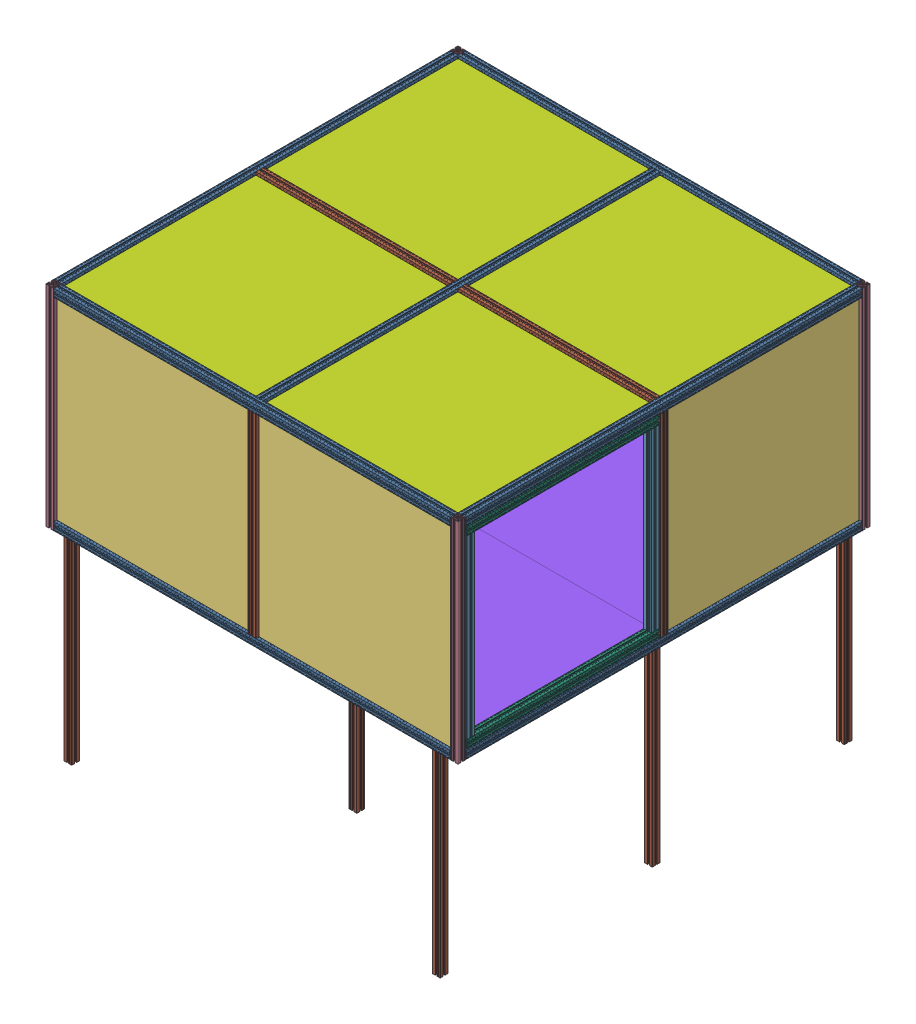
SolidWorks assembly Arena_Mod_Clean, configuration Valor predeterminado. Lengths in mm.
Overall size (2080 2040 2080).
64 component instances, 8 part files, 4 mates.
Components (placement in the parent):
- Lateral_S_Porta_Mod2-1: Lateral_S_Porta_Mod2 [Valor predeterminado] at (857.6684 -517.9892 5370.6056) size (2020 2040 40)
  - Perfil_Alum_4x4x200-1: Perfil_Alum_4x4x200 [Valor predeterminado] at (40.4856 -17.0967 -270.6056) x (0 0 -1) z (1 0 0) size (40 40 2000)
  - Perfil_Alum_4x4x200-2: Perfil_Alum_4x4x200 [Valor predeterminado] at (40.4856 1002.9033 -270.6056) x (0 0 -1) z (1 0 0) size (40 40 2000)
  - Perfil_Alum_4x4x98-1: Perfil_Alum_4x4x98 [Valor predeterminado] at (40.4856 492.9033 -270.6056) x (1 0 0) z (0 -1 0) size (40 40 980)
  - Policarbonato 1x1-1: Policarbonato 1x1 [Valor predeterminado] at (550.4856 492.9033 -270.6056) size (1000 1000 6)
  - Policarbonato 1x1-2: Policarbonato 1x1 [Valor predeterminado] at (-469.5144 492.9033 -270.6056) size (1000 1000 6)
  - Perfil_Alum_4x4x98-2: Perfil_Alum_4x4x98 [Valor predeterminado] at (-889.5144 -527.0967 -270.6056) x (1 0 0) z (0 -1 0) size (40 40 980)
  - Perfil_Alum_4x4x98-3: Perfil_Alum_4x4x98 [Valor predeterminado] at (970.4856 -527.0967 -270.6056) x (1 0 0) z (0 -1 0) size (40 40 980)
- Lateral_C_Porta_Mod2-2: Lateral_C_Porta_Mod2 [Valor predeterminado] at (1960.4084 -532.8569 2080) size (40 1060 2080)
  - Perfil_Alum_4x4x200-1: Perfil_Alum_4x4x200 [Valor predeterminado] at (-42.2544 -2.229 2000) size (40 40 2000)
  - Perfil_Alum_4x4x106-1: Perfil_Alum_4x4x106 [Valor predeterminado] at (-42.2544 507.771 3020) x (1 0 0) z (0 -1 0) size (40 40 1060)
  - Perfil_Alum_4x4x98-1: Perfil_Alum_4x4x98 [Valor predeterminado] at (-42.2544 507.771 2000) x (1 0 0) z (0 -1 0) size (40 40 980)
  - Perfil_Alum_4x4x106-2: Perfil_Alum_4x4x106 [Valor predeterminado] at (-42.2544 507.771 980) x (1 0 0) z (0 -1 0) size (40 40 1060)
  - Perfil_Alum_4x4x200-2: Perfil_Alum_4x4x200 [Valor predeterminado] at (-42.2544 1017.771 2000) size (40 40 2000)
  - Porta_Mod_Clean-1: Porta_Mod_Clean [Valor predeterminado] at (-25.965 113.1173 1603.2592) size (40 970 970)
    - Perfil_Alum_4x4x89-1: Perfil_Alum_4x4x89 [Valor predeterminado] at (-16.2893 394.6537 1371.7408) x (1 0 0) z (0 -1 0) size (40 40 890)
    - Perfil_Alum_4x4x97-1: Perfil_Alum_4x4x97 [Valor predeterminado] at (-16.2893 -70.3463 906.7408) size (40 40 970)
    - Perfil_Alum_4x4x97-2: Perfil_Alum_4x4x97 [Valor predeterminado] at (-16.2893 859.6537 906.7408) size (40 40 970)
    - Perfil_Alum_4x4x89-2: Perfil_Alum_4x4x89 [Valor predeterminado] at (-16.2893 394.6537 441.7408) x (1 0 0) z (0 -1 0) size (40 40 890)
  - Policarbonato 1x1-1: Policarbonato 1x1 [Valor predeterminado] at (-42.2544 507.771 1490) x (0 0 -1) z (1 0 0) size (1000 1000 6)
- Lateral_S_Porta_Mod2-2: Lateral_S_Porta_Mod2 [Valor predeterminado] at (857.6684 -517.9892 3330.6056) size (2020 2040 40)
  - Perfil_Alum_4x4x200-1: Perfil_Alum_4x4x200 [Valor predeterminado] at (40.4856 -17.0967 -270.6056) x (0 0 -1) z (1 0 0) size (40 40 2000)
  - Perfil_Alum_4x4x200-2: Perfil_Alum_4x4x200 [Valor predeterminado] at (40.4856 1002.9033 -270.6056) x (0 0 -1) z (1 0 0) size (40 40 2000)
  - Perfil_Alum_4x4x98-1: Perfil_Alum_4x4x98 [Valor predeterminado] at (40.4856 492.9033 -270.6056) x (1 0 0) z (0 -1 0) size (40 40 980)
  - Policarbonato 1x1-1: Policarbonato 1x1 [Valor predeterminado] at (550.4856 492.9033 -270.6056) size (1000 1000 6)
  - Policarbonato 1x1-2: Policarbonato 1x1 [Valor predeterminado] at (-469.5144 492.9033 -270.6056) size (1000 1000 6)
  - Perfil_Alum_4x4x98-2: Perfil_Alum_4x4x98 [Valor predeterminado] at (-889.5144 -527.0967 -270.6056) x (1 0 0) z (0 -1 0) size (40 40 980)
  - Perfil_Alum_4x4x98-3: Perfil_Alum_4x4x98 [Valor predeterminado] at (970.4856 -527.0967 -270.6056) x (1 0 0) z (0 -1 0) size (40 40 980)
- Teto_Mod_Clean-1: Teto_Mod_Clean [Valor predeterminado] at (1160.5083 2484.9141 4086.7617) size (2020 40 2020)
  - Perfil_Alum_4x4x200-1: Perfil_Alum_4x4x200 [Valor predeterminado] at (-262.3542 -2000 -6.7617) size (40 40 2000)
  - Perfil_Alum_4x4x98-1: Perfil_Alum_4x4x98 [Valor predeterminado] at (-772.3542 -2000 -6.7617) x (0 0 -1) z (1 0 0) size (40 40 980)
  - Perfil_Alum_4x4x98-2: Perfil_Alum_4x4x98 [Valor predeterminado] at (247.6458 -2000 -6.7617) x (0 0 -1) z (1 0 0) size (40 40 980)
  - Policarbonato_Teto-1: Policarbonato_Teto [Valor predeterminado] at (-772.3542 -2000 -516.7617) size (1000 6 1000)
  - Policarbonato_Teto-2: Policarbonato_Teto [Valor predeterminado] at (-772.3542 -2000 503.2383) x (0 0 -1) z (1 0 0) size (1000 6 1000)
  - Policarbonato_Teto-3: Policarbonato_Teto [Valor predeterminado] at (247.6458 -2000 503.2383) x (-1 0 0) z (0 0 -1) size (1000 6 1000)
  - Policarbonato_Teto-4: Policarbonato_Teto [Valor predeterminado] at (247.6458 -2000 -516.7617) x (0 0 1) z (-1 0 0) size (1000 6 1000)
- Lateral_C_Porta_Mod2-3: Lateral_C_Porta_Mod2 [Valor predeterminado] at (-164.1003 -532.8569 6080) x (-1 0 0) z (0 0 -1) size (40 1060 2080)
  - Perfil_Alum_4x4x200-1: Perfil_Alum_4x4x200 [Valor predeterminado] at (-42.2544 -2.229 2000) size (40 40 2000)
  - Perfil_Alum_4x4x106-1: Perfil_Alum_4x4x106 [Valor predeterminado] at (-42.2544 507.771 3020) x (1 0 0) z (0 -1 0) size (40 40 1060)
  - Perfil_Alum_4x4x98-1: Perfil_Alum_4x4x98 [Valor predeterminado] at (-42.2544 507.771 2000) x (1 0 0) z (0 -1 0) size (40 40 980)
  - Perfil_Alum_4x4x106-2: Perfil_Alum_4x4x106 [Valor predeterminado] at (-42.2544 507.771 980) x (1 0 0) z (0 -1 0) size (40 40 1060)
  - Perfil_Alum_4x4x200-2: Perfil_Alum_4x4x200 [Valor predeterminado] at (-42.2544 1017.771 2000) size (40 40 2000)
  - Porta_Mod_Clean-1: Porta_Mod_Clean [Valor predeterminado] at (-25.965 113.1173 1603.2592) size (40 970 970)
    - Perfil_Alum_4x4x89-1: Perfil_Alum_4x4x89 [Valor predeterminado] at (-16.2893 394.6537 1371.7408) x (1 0 0) z (0 -1 0) size (40 40 890)
    - Perfil_Alum_4x4x97-1: Perfil_Alum_4x4x97 [Valor predeterminado] at (-16.2893 -70.3463 906.7408) size (40 40 970)
    - Perfil_Alum_4x4x97-2: Perfil_Alum_4x4x97 [Valor predeterminado] at (-16.2893 859.6537 906.7408) size (40 40 970)
    - Perfil_Alum_4x4x89-2: Perfil_Alum_4x4x89 [Valor predeterminado] at (-16.2893 394.6537 441.7408) x (1 0 0) z (0 -1 0) size (40 40 890)
  - Policarbonato 1x1-1: Policarbonato 1x1 [Valor predeterminado] at (-42.2544 507.771 1490) x (0 0 -1) z (1 0 0) size (1000 1000 6)
- Fundo_Mod_Clean-1: Fundo_Mod_Clean [Valor predeterminado] at (822.4229 -2535.0859 4054.3055) size (2030 1022.12 2030)
  - Perfil_Alum_4x4x200-1: Perfil_Alum_4x4x200 [Valor predeterminado] at (75.7311 2000 25.6945) size (40 40 2000)
  - Perfil_Alum_4x4x98-1: Perfil_Alum_4x4x98 [Valor predeterminado] at (-434.2689 2000 25.6945) x (0 0 -1) z (1 0 0) size (40 40 980)
  - Perfil_Alum_4x4x98-2: Perfil_Alum_4x4x98 [Valor predeterminado] at (586.3147 2000 25.6943) x (0 0 -1) z (1 0 0) size (40 40 980)
  - Perfil_Alum_4x4x98-3: Perfil_Alum_4x4x98 [Valor predeterminado] at (-434.2689 2000 -484.3055) x (0 0 -1) z (1 0 0) size (40 40 980)
  - Perfil_Alum_4x4x98-4: Perfil_Alum_4x4x98 [Valor predeterminado] at (585.7311 2000 -484.3055) x (0 0 -1) z (1 0 0) size (40 40 980)
  - Perfil_Alum_4x4x98-5: Perfil_Alum_4x4x98 [Valor predeterminado] at (-434.2689 2000 535.6945) x (0 0 -1) z (1 0 0) size (40 40 980)
  - Perfil_Alum_4x4x98-6: Perfil_Alum_4x4x98 [Valor predeterminado] at (585.7311 2000 535.6945) x (0 0 -1) z (1 0 0) size (40 40 980)
  - Chapa_Fundo_Mod_Clean-1: Chapa_Fundo_Mod_Clean [Valor predeterminado] at (583.2024 2021.1231 -481.8055) size (1015 2 1015)
  - Chapa_Fundo_Mod_Clean-2: Chapa_Fundo_Mod_Clean [Valor predeterminado] at (-431.7976 2021.1231 -481.8055) x (0 0 -1) z (1 0 0) size (1015 2 1015)
  - Chapa_Fundo_Mod_Clean-3: Chapa_Fundo_Mod_Clean [Valor predeterminado] at (-431.7976 2021.1231 533.1945) x (-1 0 0) z (0 0 -1) size (1015 2 1015)
  - Chapa_Fundo_Mod_Clean-4: Chapa_Fundo_Mod_Clean [Valor predeterminado] at (583.2024 2021.1231 533.1945) x (0 0 1) z (-1 0 0) size (1015 2 1015)
  - Perfil_Alum_4x4x98-7: Perfil_Alum_4x4x98 [Valor predeterminado] at (75.7311 1490 -484.3055) x (1 0 0) z (0 -1 0) size (40 40 980)
  - Perfil_Alum_4x4x98-8: Perfil_Alum_4x4x98 [Valor predeterminado] at (1056.3147 1490 25.6943) x (1 0 0) z (0 -1 0) size (40 40 980)
  - Perfil_Alum_4x4x98-9: Perfil_Alum_4x4x98 [Valor predeterminado] at (-904.2689 1490 25.6945) x (1 0 0) z (0 -1 0) size (40 40 980)
  - Perfil_Alum_4x4x98-10: Perfil_Alum_4x4x98 [Valor predeterminado] at (75.7311 1490 535.6945) x (1 0 0) z (0 -1 0) size (40 40 980)
Mates (geometry in assembly coordinates):
- Coincidente2: coincident: point of Lateral_S_Porta_Mod2-1/Perfil_Alum_4x4x200-2; unknown of Lateral_C_Porta_Mod2-2/Perfil_Alum_4x4x106-1
- Coincidente3: coincident: unknown of Lateral_C_Porta_Mod2-2/Perfil_Alum_4x4x106-2; unknown of Lateral_S_Porta_Mod2-2/Perfil_Alum_4x4x200-2
- Coincidente4: coincident: unknown of Lateral_S_Porta_Mod2-1/Perfil_Alum_4x4x200-2; unknown of Lateral_C_Porta_Mod2-3/Perfil_Alum_4x4x106-2
- Distância1: distance = 980 mm: line of Lateral_C_Porta_Mod2-3/Perfil_Alum_4x4x200-1 through (-101.8459 -549.4859 3080) axis (0 -1 0); line of Fundo_Mod_Clean-1/Perfil_Alum_4x4x98-1 through (-101.8459 -553.586 4060) axis (0 1 0)
